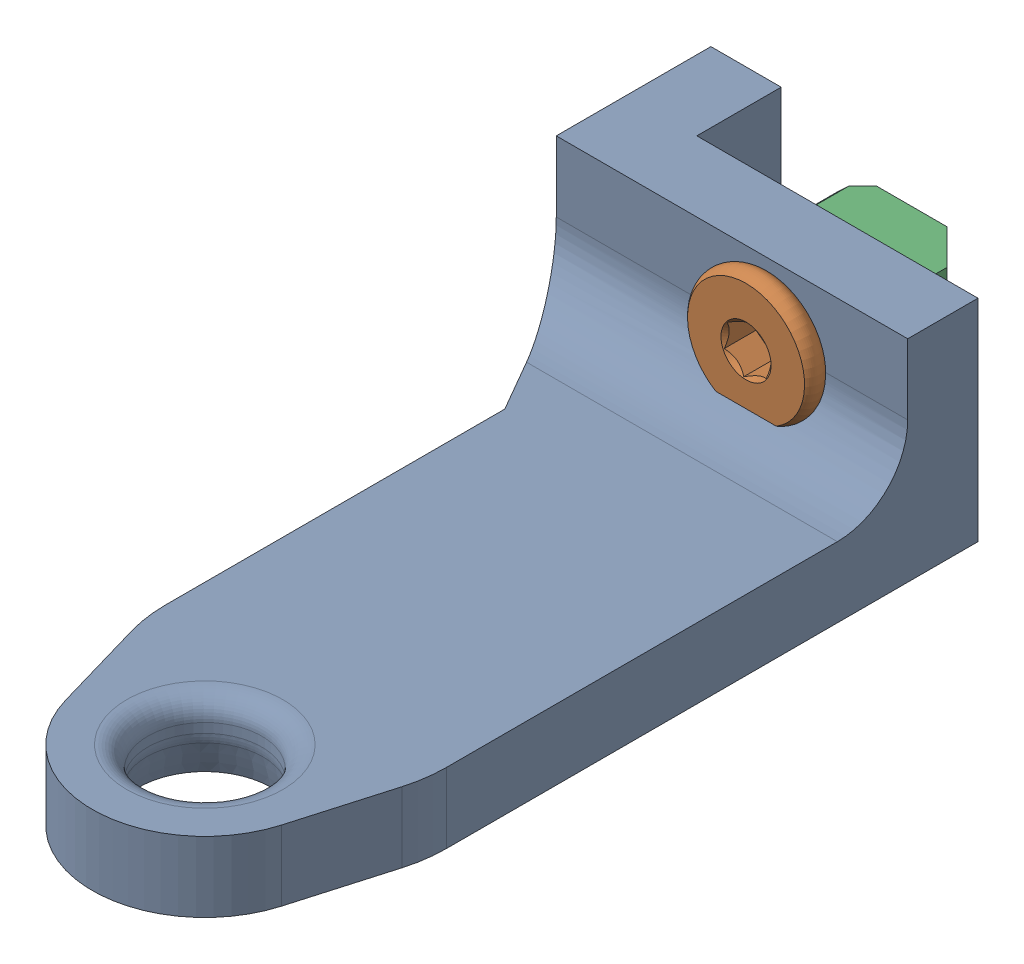
SolidWorks assembly back_leadscrew_retainer, configuration Default. Lengths in mm.
Overall size (25 15.02 59).
3 component instances, 3 part files, 0 mates.
Components (placement in the parent):
- back_leadscrew_retainer_Back Leadscrew Retainer-1: back_leadscrew_retainer_Back Leadscrew Retainer [Default] at (-10 0 82.6328) size (25 15 59)
- m5_low_profile_screw_template_M5 x 10-1: m5_low_profile_screw_template_M5 x 10 [Default] at (-10 10 32.6328) x (0 0 -1) z (0.992361 -0.12337 0) size (11.62 9 9)
- m5_locking_t_nut_20x20_generic-1: m5_locking_t_nut_20x20_generic [Default] at (-10 13 32.3328) x (1 0 0) z (0 -1 0) size (10 4.5 6)
